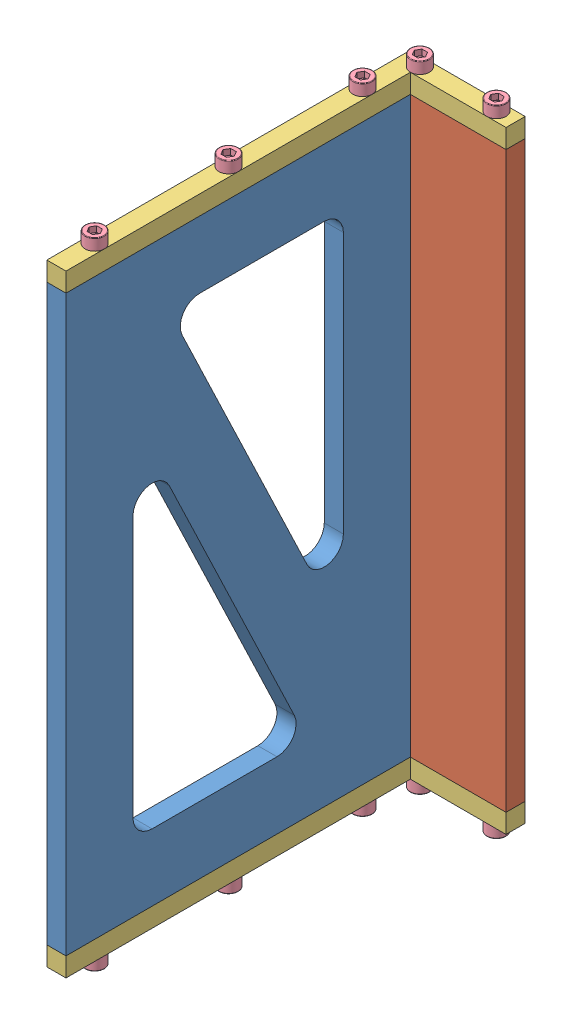
SolidWorks assembly testee2, configuration Default. Lengths in mm.
Overall size (60 332 196).
18 component instances, 4 part files, 32 mates.
Components (placement in the parent):
- L1-1: L1 [Default] at (59.529 -21.8534 175.8837) size (60 300 190)
  - PLACA L2-1: PLACA L2 [Default] at (0 286.0775 10) x (0 0 1) z (0 1 0) size (180 10 300)
  - PLACA L1de-1: PLACA L1de [Default] at (0 -13.9225 0) size (60 300 10)
- pecinha2-1: pecinha2 [Default] at (69.529 264.2241 185.8837) x (-1 0 0) z (0 0 -1) size (60 10 190)
- pecinha2-2: pecinha2 [Default] at (69.529 -45.7759 185.8837) x (-1 0 0) z (0 0 -1) size (60 10 190)
- socket head cap screw_iso-1: socket head cap screw_iso [ISO 4762 M6 x 20 - 20N] at (109.529 280.2241 180.8837) x (0 -1 0) z (0 0 1) size (26 10 10)
- socket head cap screw_iso-2: socket head cap screw_iso [ISO 4762 M6 x 20 - 20N] at (69.529 280.2241 180.8837) x (0 -1 0) z (0 0 1) size (26 10 10)
- socket head cap screw_iso-3: socket head cap screw_iso [ISO 4762 M6 x 20 - 20N] at (64.529 280.2241 205.8837) x (0 -1 0) z (0 0 1) size (26 10 10)
- socket head cap screw_iso-4: socket head cap screw_iso [ISO 4762 M6 x 20 - 20N] at (64.529 280.2241 275.8837) x (0 -1 0) z (0 0 1) size (26 10 10)
- socket head cap screw_iso-5: socket head cap screw_iso [ISO 4762 M6 x 20 - 20N] at (64.529 280.2241 345.8837) x (0 -1 0) z (0 0 1) size (26 10 10)
- socket head cap screw_iso-6: socket head cap screw_iso [ISO 4762 M6 x 20 - 20N] at (64.529 214.2241 169.8837) x (0 0 1) z (-1 0 0) size (26 10 10)
- socket head cap screw_iso-7: socket head cap screw_iso [ISO 4762 M6 x 20 - 20N] at (64.529 114.2241 169.8837) x (0 0 1) z (-1 0 0) size (26 10 10)
- socket head cap screw_iso-8: socket head cap screw_iso [ISO 4762 M6 x 20 - 20N] at (64.529 14.2241 169.8837) x (0 0 1) z (-1 0 0) size (26 10 10)
- socket head cap screw_iso-9: socket head cap screw_iso [ISO 4762 M6 x 20 - 20N] at (109.529 -51.7759 180.8837) x (0 1 0) z (0 0 1) size (26 10 10)
- socket head cap screw_iso-10: socket head cap screw_iso [ISO 4762 M6 x 20 - 20N] at (69.529 -51.7759 180.8837) x (0 1 0) z (0 0 1) size (26 10 10)
- socket head cap screw_iso-11: socket head cap screw_iso [ISO 4762 M6 x 20 - 20N] at (64.529 -51.7759 205.8837) x (0 1 0) z (0 0 1) size (26 10 10)
- socket head cap screw_iso-12: socket head cap screw_iso [ISO 4762 M6 x 20 - 20N] at (64.529 -51.7759 275.8837) x (0 1 0) z (0 0 1) size (26 10 10)
- socket head cap screw_iso-13: socket head cap screw_iso [ISO 4762 M6 x 20 - 20N] at (64.529 -51.7759 345.8837) x (0 1 0) z (0 0 1) size (26 10 10)
Mates (geometry in assembly coordinates):
- Coincident1: coincident aligned: plane of L1-1/PLACA L1de-1 through (59.529 -35.7759 175.8837) normal (0 0 -1); plane of pecinha2-1 through (59.529 274.2241 175.8837) normal (0 0 -1)
- Coincident3: coincident anti-aligned: plane of L1-1/PLACA L1de-1 through (59.529 264.2241 185.8837) normal (0 1 0); plane of pecinha2-1 through (69.529 264.2241 185.8837) normal (0 -1 0)
- Coincident4: coincident aligned: plane of L1-1/PLACA L2-1 through (59.529 264.2241 185.8837) normal (-1 0 0); plane of pecinha2-1 through (59.529 274.2241 365.8837) normal (-1 0 0)
- Coincident5: coincident aligned: plane of L1-1/PLACA L1de-1 through (59.529 -35.7759 175.8837) normal (0 0 -1); plane of pecinha2-2 through (59.529 -35.7759 175.8837) normal (0 0 -1)
- Coincident6: coincident aligned: plane of L1-1/PLACA L2-1 through (69.529 264.2241 185.8837) normal (1 0 0); plane of pecinha2-2 through (69.529 -35.7759 185.8837) normal (1 0 0)
- Coincident7: coincident anti-aligned: plane of L1-1/PLACA L2-1 through (69.529 -35.7759 185.8837) normal (0 -1 0); plane of pecinha2-2 through (69.529 -35.7759 185.8837) normal (0 1 0)
- Concentric1: concentric aligned: cylinder of pecinha2-1 through (109.529 264.2241 180.8837) axis (0 1 0) radius 3.25; cylinder of socket head cap screw_iso-1 through (109.529 311.9741 180.8837) axis (0 1 0) radius 5
- Coincident8: coincident anti-aligned: plane of pecinha2-1 through (69.529 274.2241 185.8837) normal (0 1 0); plane of socket head cap screw_iso-1 through (114.529 274.2241 180.8837) normal (0 -1 0)
- Concentric2: concentric aligned: cylinder of pecinha2-1 through (69.529 264.2241 180.8837) axis (0 1 0) radius 3.25; cylinder of socket head cap screw_iso-2 through (69.529 311.9741 180.8837) axis (0 1 0) radius 5
- Coincident9: coincident anti-aligned: plane of pecinha2-1 through (69.529 274.2241 185.8837) normal (0 1 0); plane of socket head cap screw_iso-2 through (74.529 274.2241 180.8837) normal (0 -1 0)
- Concentric3: concentric aligned: cylinder of pecinha2-1 through (64.529 264.2241 205.8837) axis (0 1 0) radius 3.25; cylinder of socket head cap screw_iso-3 through (64.529 311.9741 205.8837) axis (0 1 0) radius 5
- Coincident10: coincident anti-aligned: plane of pecinha2-1 through (69.529 274.2241 185.8837) normal (0 1 0); plane of socket head cap screw_iso-3 through (69.529 274.2241 205.8837) normal (0 -1 0)
- Concentric4: concentric aligned: cylinder of pecinha2-1 through (64.529 264.2241 275.8837) axis (0 1 0) radius 3.25; cylinder of socket head cap screw_iso-4 through (64.529 311.9741 275.8837) axis (0 1 0) radius 5
- Coincident11: coincident anti-aligned: plane of pecinha2-1 through (69.529 274.2241 185.8837) normal (0 1 0); plane of socket head cap screw_iso-4 through (69.529 274.2241 275.8837) normal (0 -1 0)
- Concentric5: concentric aligned: cylinder of pecinha2-1 through (64.529 264.2241 345.8837) axis (0 1 0) radius 3.25; cylinder of socket head cap screw_iso-5 through (64.529 311.9741 345.8837) axis (0 1 0) radius 5
- Coincident12: coincident anti-aligned: plane of pecinha2-1 through (69.529 274.2241 185.8837) normal (0 1 0); plane of socket head cap screw_iso-5 through (69.529 274.2241 345.8837) normal (0 -1 0)
- Concentric6: concentric aligned: cylinder of L1-1/PLACA L1de-1 through (64.529 214.2241 175.8837) axis (0 0 -1) radius 3.3; cylinder of socket head cap screw_iso-6 through (64.529 214.2241 138.1337) axis (0 0 -1) radius 5
- Coincident13: coincident anti-aligned: plane of L1-1/PLACA L1de-1 through (59.529 -35.7759 175.8837) normal (0 0 -1); plane of socket head cap screw_iso-6 through (64.529 219.2241 175.8837) normal (0 0 1)
- Concentric7: concentric aligned: cylinder of L1-1/PLACA L1de-1 through (64.529 114.2241 175.8837) axis (0 0 -1) radius 3.3; cylinder of socket head cap screw_iso-7 through (64.529 114.2241 138.1337) axis (0 0 -1) radius 5
- Coincident14: coincident anti-aligned: plane of L1-1/PLACA L1de-1 through (59.529 -35.7759 175.8837) normal (0 0 -1); plane of socket head cap screw_iso-7 through (64.529 119.2241 175.8837) normal (0 0 1)
- Concentric8: concentric aligned: cylinder of L1-1/PLACA L1de-1 through (64.529 14.2241 175.8837) axis (0 0 -1) radius 3.3; cylinder of socket head cap screw_iso-8 through (64.529 14.2241 138.1337) axis (0 0 -1) radius 5
- Coincident15: coincident anti-aligned: plane of L1-1/PLACA L1de-1 through (59.529 -35.7759 175.8837) normal (0 0 -1); plane of socket head cap screw_iso-8 through (64.529 19.2241 175.8837) normal (0 0 1)
- Concentric9: concentric anti-aligned: cylinder of pecinha2-2 through (109.529 -45.7759 180.8837) axis (0 1 0) radius 3.25; cylinder of socket head cap screw_iso-9 through (109.529 -83.5259 180.8837) axis (0 -1 0) radius 5
- Coincident16: coincident anti-aligned: plane of pecinha2-2 through (69.529 -45.7759 185.8837) normal (0 -1 0); plane of socket head cap screw_iso-9 through (104.529 -45.7759 180.8837) normal (0 1 0)
- Concentric10: concentric anti-aligned: cylinder of pecinha2-2 through (69.529 -45.7759 180.8837) axis (0 1 0) radius 3.25; cylinder of socket head cap screw_iso-10 through (69.529 -83.5259 180.8837) axis (0 -1 0) radius 5
- Coincident17: coincident anti-aligned: plane of pecinha2-2 through (69.529 -45.7759 185.8837) normal (0 -1 0); plane of socket head cap screw_iso-10 through (64.529 -45.7759 180.8837) normal (0 1 0)
- Concentric11: concentric anti-aligned: cylinder of pecinha2-2 through (64.529 -45.7759 205.8837) axis (0 1 0) radius 3.25; cylinder of socket head cap screw_iso-11 through (64.529 -83.5259 205.8837) axis (0 -1 0) radius 5
- Coincident18: coincident anti-aligned: plane of pecinha2-2 through (69.529 -45.7759 185.8837) normal (0 -1 0); plane of socket head cap screw_iso-11 through (59.529 -45.7759 205.8837) normal (0 1 0)
- Concentric12: concentric anti-aligned: cylinder of pecinha2-2 through (64.529 -45.7759 275.8837) axis (0 1 0) radius 3.25; cylinder of socket head cap screw_iso-12 through (64.529 -83.5259 275.8837) axis (0 -1 0) radius 5
- Coincident19: coincident anti-aligned: plane of pecinha2-2 through (69.529 -45.7759 185.8837) normal (0 -1 0); plane of socket head cap screw_iso-12 through (59.529 -45.7759 275.8837) normal (0 1 0)
- Concentric13: concentric anti-aligned: cylinder of pecinha2-2 through (64.529 -45.7759 345.8837) axis (0 1 0) radius 3.25; cylinder of socket head cap screw_iso-13 through (64.529 -83.5259 345.8837) axis (0 -1 0) radius 5
- Coincident20: coincident anti-aligned: plane of pecinha2-2 through (69.529 -45.7759 185.8837) normal (0 -1 0); plane of socket head cap screw_iso-13 through (59.529 -45.7759 345.8837) normal (0 1 0)
